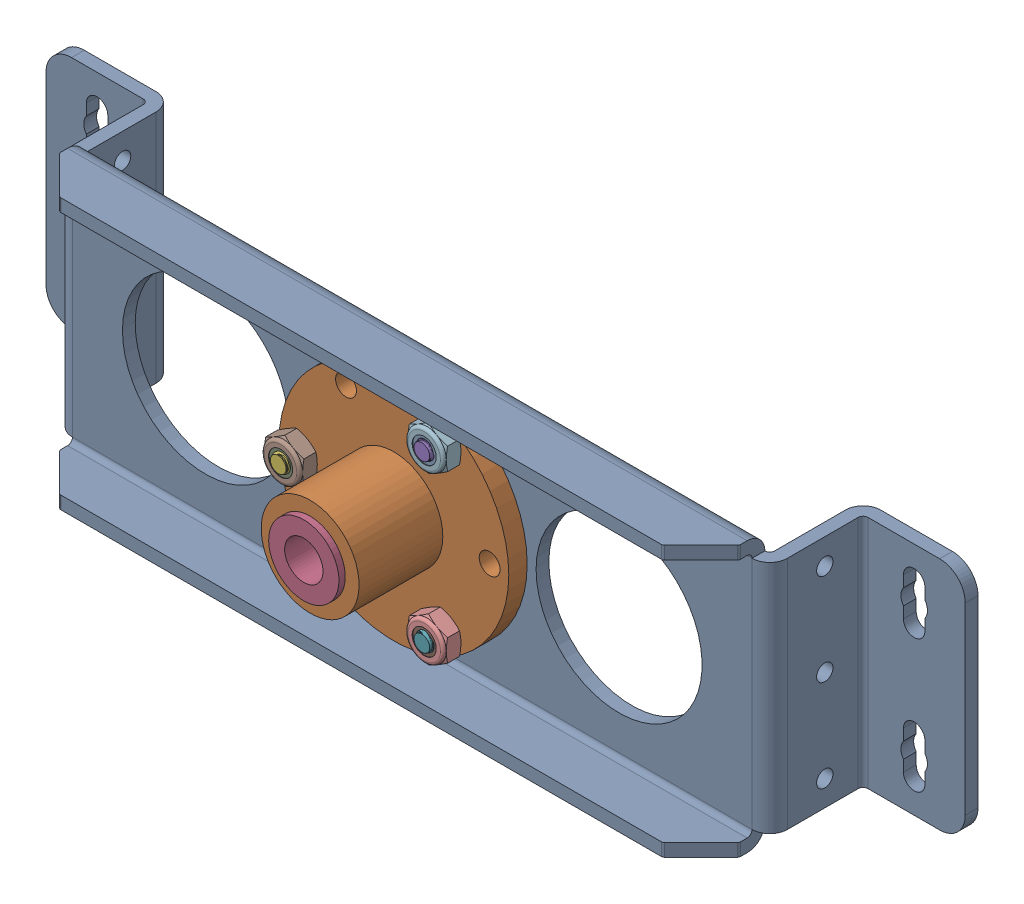
SolidWorks assembly ws_pivot_support_asm_revc.iam (LevelofDetail1), configuration Default. Lengths in mm.
Overall size (228.6 67.21 53.37).
16 component instances, 6 part files, 0 mates.
Components (placement in the parent):
- ws_pivot_bracket_revc-1: ws_pivot_bracket_revc [Default] at origin size (228.6 67.21 39.09)
- AM_universal-hub-1: AM_universal-hub [Default] at (66.8241 17.5662 20.7821) x (0 0 1) z (-1 0 0) size (25.4 57.15 57.15)
- 863_bronze_.5_bushing-1: 863_bronze_.5_bushing [Default] at (66.8241 17.5662 1.6002) x (0 0 1) z (-1 0 0) size (12.7 17.46 17.46)
- 863_bronze_.5_bushing-2: 863_bronze_.5_bushing [Default] at (66.8241 17.5662 30.1498) x (0 0 -1) z (1 0 0) size (12.7 17.46 17.46)
- fhcs_91253A242-1: fhcs_91253A242 [Default] at (78.7304 38.1884 3.2258) x (0.989669 0.143368 0) z (0 0 -1) size (10.32 10.32 12.88)
- fhcs_91253A242-2: fhcs_91253A242 [Default] at (43.0116 17.5662 3.2258) x (-0.618995 0.785395 0) z (0 0 -1) size (10.32 10.32 12.88)
- fhcs_91253A242-3: fhcs_91253A242 [Default] at (78.7304 -3.0561 3.2258) x (-0.370675 -0.928763 0) z (0 0 -1) size (10.32 10.32 12.88)
- nylon_lock_nut_90633A011-1: nylon_lock_nut_90633A011 [Default] at (43.0116 17.5662 7.747) x (1 0 0) z (0 -1 0) size (9.53 4.52 11)
  - NONE-1: NONE [Default] at origin size (9.53 4.52 11)
  - NONE1-1: NONE1 [Default] at origin size (9.06 0.43 9.06)
- nylon_lock_nut_90633A011-2: nylon_lock_nut_90633A011 [Default] at (78.7304 -3.0561 7.747) x (-0.5 0.866025 0) z (0.866025 0.5 0) size (9.53 4.52 11)
  - NONE-1: NONE [Default] at origin size (9.53 4.52 11)
  - NONE1-1: NONE1 [Default] at origin size (9.06 0.43 9.06)
- nylon_lock_nut_90633A011-3: nylon_lock_nut_90633A011 [Default] at (78.7304 38.1884 7.747) x (-0.5 -0.866025 0) z (-0.866025 0.5 0) size (9.53 4.52 11)
  - NONE-1: NONE [Default] at origin size (9.53 4.52 11)
  - NONE1-1: NONE1 [Default] at origin size (9.06 0.43 9.06)
